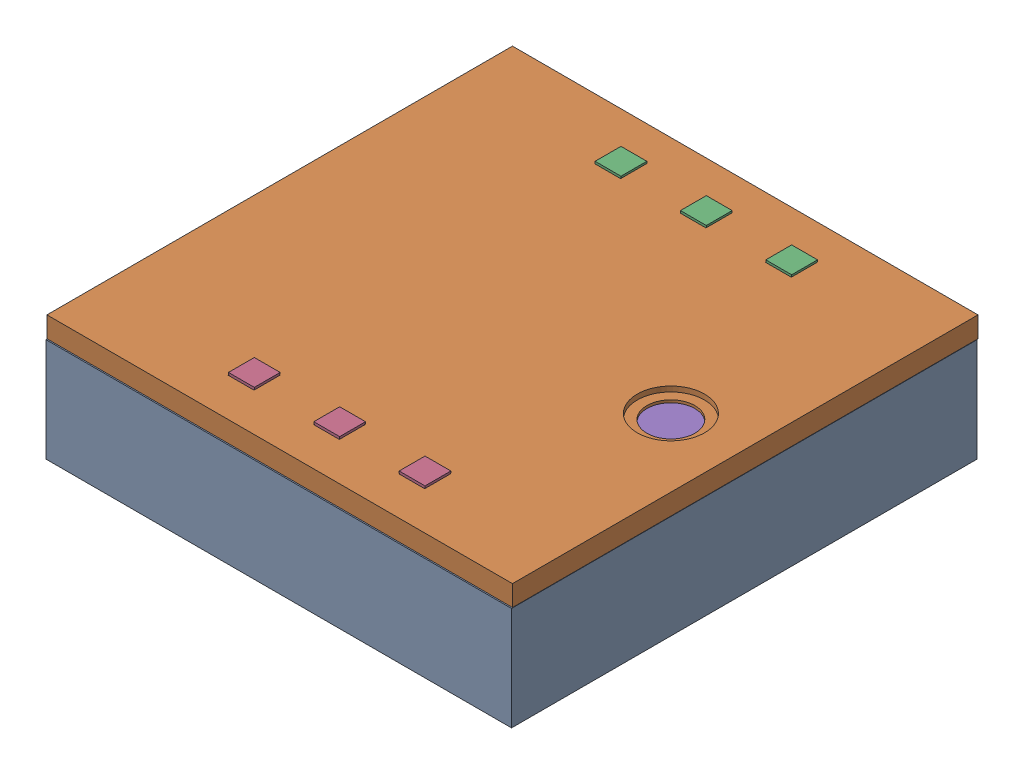
SolidWorks assembly Box Assembly, configuration Default. Lengths in mm.
Overall size (90.07 24.51 90.12).
6 component instances, 5 part files, 0 mates.
Components (placement in the parent):
- DecibilityBox2-1: DecibilityBox2 [Default] at origin size (90 23 90)
- DecibilityBox Lid-2: DecibilityBox Lid [Default] at (0.0655 24.1335 -0.1158) x (-1 0 0) z (0 0 1) size (90 4 90)
- LED Strip-1: LED Strip [Default] at (1.7157 22.0085 -35.9411) size (50 2.5 10)
- LED Strip-2: LED Strip [Default] at (1.5949 21.9789 34.8225) size (50 2.5 10)
- Breadboard-1: Breadboard [Default] at (-0.1161 1.6687 1.0742) x (-1 0 0) z (0 0 -1) size (85.5 10.7 56.5)
- ESP32 Dev-1: ESP32 Dev [Default] at (-19.7611 9.9835 0.7417) size (40.38 7 25.4)
